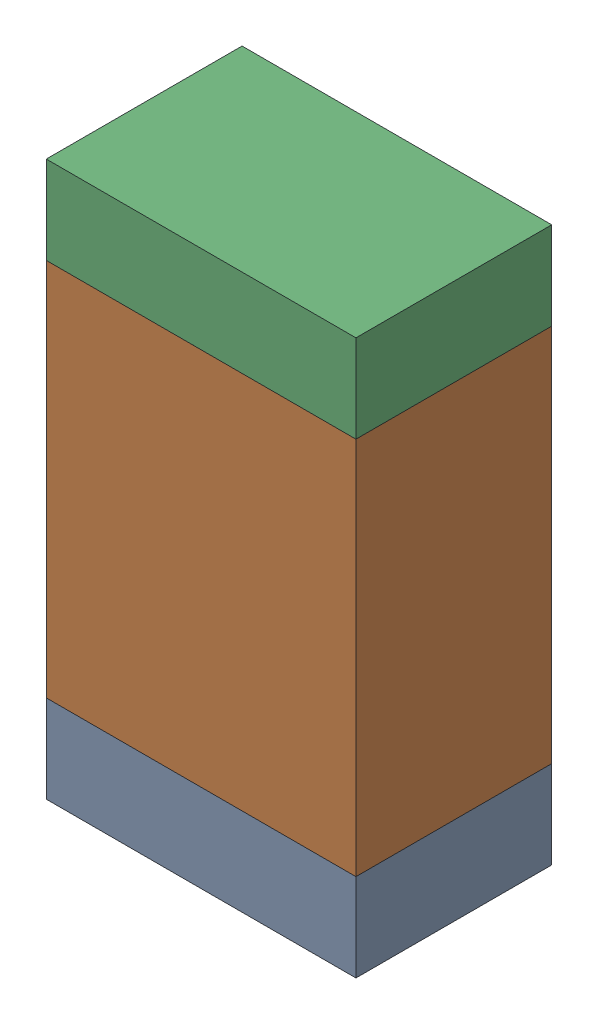
SolidWorks assembly R04, configuration Default. Lengths in mm.
Overall size (0.95 1.7 0.6).
6 component instances, 2 part files, 0 mates.
Components (placement in the parent):
- 959206216-1: 959206216 [Default] at (141.478 81.581 0) size (0.95 0.27 0.6)
  - Extruded-1: Extruded [Default] at origin size (0.95 0.27 0.6)
- 959206352-1: 959206352 [Default] at (141.478 82.296 0) size (0.95 1.16 0.6)
  - Extruded-1-1: Extruded-1 [Default] at origin size (0.95 1.16 0.6)
- 959206216-2: 959206216 [Default] at (141.478 83.011 0) size (0.95 0.27 0.6)
  - Extruded-1: Extruded [Default] at origin size (0.95 0.27 0.6)
